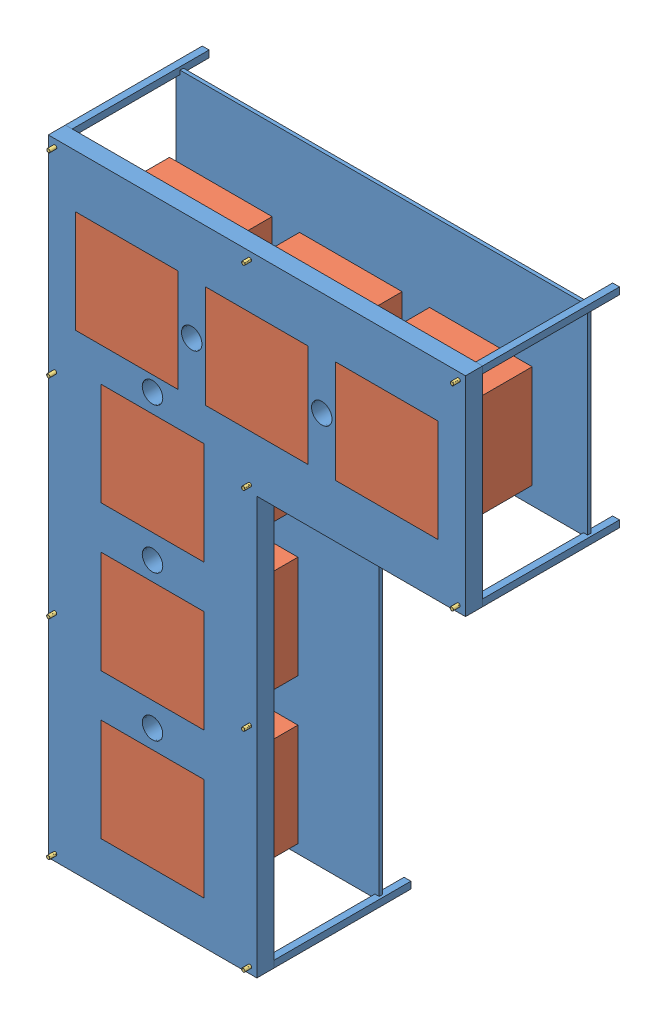
SolidWorks assembly Assemb_rack_small, configuration Default. Lengths in mm.
Overall size (2438.4 3657.6 941.92).
17 component instances, 3 part files, 38 mates.
Components (placement in the parent):
- Rack_small-1: Rack_small [Default] at (-488.5042 3287.9022 2848.7544) size (2438.4 3657.6 900)
- vent_for_RACKS-1: vent_for_RACKS [Default] at (1029.8958 2378.7022 2948.7544) x (0 0 1) z (-1 0 0) size (550 600 600)
- vent_for_RACKS-2: vent_for_RACKS [Default] at (269.8958 2378.7022 2948.7544) x (0 0 1) z (-1 0 0) size (550 600 600)
- vent_for_RACKS-3: vent_for_RACKS [Default] at (420.6958 -119.6978 2948.7544) x (0 0 1) z (-1 0 0) size (550 600 600)
- vent_for_RACKS-4: vent_for_RACKS [Default] at (420.6958 730.3022 2948.7544) x (0 0 1) z (-1 0 0) size (550 600 600)
- vent_for_RACKS-5: vent_for_RACKS [Default] at (420.6958 1580.3022 2948.7544) x (0 0 1) z (-1 0 0) size (550 600 600)
- vent_for_RACKS-6: vent_for_RACKS [Default] at (1789.8958 2378.7022 2948.7544) x (0 0 1) z (-1 0 0) size (550 600 600)
- Bolt-4: Bolt [Default] at (-448.5042 2108.7022 2849.734) x (0 0 -1) z (-0.276507 -0.961012 0) size (84.07 21.62 21.62)
- Bolt-5: Bolt [Default] at (-448.5042 3247.9022 2849.734) x (0 0 -1) z (1 0 0) size (84.07 21.62 21.62)
- Bolt-11: Bolt [Default] at (690.6958 2108.7022 3047.5415) x (0 0 1) z (0.34319 0.939266 0) size (84.07 21.62 21.62)
- Bolt-12: Bolt [Default] at (690.6958 889.5022 3047.5415) x (0 0 1) z (0.926679 0.375854 0) size (84.07 21.62 21.62)
- Bolt-13: Bolt [Default] at (-448.5042 889.5022 3047.5415) x (0 0 1) z (0.919241 0.393696 0) size (84.07 21.62 21.62)
- Bolt-14: Bolt [Default] at (690.6958 -329.6978 3047.5415) x (0 0 1) z (0.023888 0.999715 0) size (84.07 21.62 21.62)
- Bolt-15: Bolt [Default] at (690.6958 3247.9022 3047.5415) x (0 0 1) z (-0.188783 0.982019 0) size (84.07 21.62 21.62)
- Bolt-16: Bolt [Default] at (-448.5042 -329.6978 3047.5415) x (0 0 1) z (0.481387 -0.876508 0) size (84.07 21.62 21.62)
- Bolt-18: Bolt [Default] at (1909.8958 2108.7022 3047.5415) x (0 0 1) z (0.573525 0.819188 0) size (84.07 21.62 21.62)
- Bolt-19: Bolt [Default] at (1909.8958 3247.9022 3047.5415) x (0 0 1) z (-0.910826 0.41279 0) size (84.07 21.62 21.62)
Mates (geometry in assembly coordinates):
- Coincident1: coincident aligned: plane of vent_for_RACKS-3 through (-179.3042 -119.6978 2398.7544) normal (0 0 -1); plane of vent_for_RACKS-4 through (-179.3042 730.3022 2398.7544) normal (0 0 -1)
- Coincident2: coincident aligned: plane of vent_for_RACKS-4 through (-179.3042 730.3022 2398.7544) normal (0 0 -1); plane of vent_for_RACKS-5 through (-179.3042 1580.3022 2398.7544) normal (0 0 -1)
- Coincident3: coincident aligned: plane of vent_for_RACKS-3 through (-179.3042 -119.6978 2398.7544) normal (0 0 -1); plane of vent_for_RACKS-6 through (1189.8958 2378.7022 2398.7544) normal (0 0 -1)
- Coincident4: coincident aligned: plane of vent_for_RACKS-2 through (-330.1042 2378.7022 2398.7544) normal (0 0 -1); plane of vent_for_RACKS-3 through (-179.3042 -119.6978 2398.7544) normal (0 0 -1)
- Coincident5: coincident aligned: plane of vent_for_RACKS-1 through (429.8958 2378.7022 2398.7544) normal (0 0 -1); plane of vent_for_RACKS-3 through (-179.3042 -119.6978 2398.7544) normal (0 0 -1)
- Coincident6: coincident aligned: plane of Rack_small-1 through (-488.5042 3287.9022 2948.7544) normal (0 0 1); plane of vent_for_RACKS-3 through (-179.3042 -119.6978 2948.7544) normal (0 0 1)
- Coincident7: coincident aligned: plane of vent_for_RACKS-3 through (-179.3042 -119.6978 2948.7544) normal (-1 0 0); plane of vent_for_RACKS-4 through (-179.3042 730.3022 2948.7544) normal (-1 0 0)
- Coincident8: coincident aligned: plane of vent_for_RACKS-3 through (-179.3042 -119.6978 2948.7544) normal (-1 0 0); plane of vent_for_RACKS-5 through (-179.3042 1580.3022 2948.7544) normal (-1 0 0)
- Coincident9: coincident aligned: plane of vent_for_RACKS-1 through (429.8958 2978.7022 2948.7544) normal (0 1 0); plane of vent_for_RACKS-6 through (1189.8958 2978.7022 2948.7544) normal (0 1 0)
- Coincident10: coincident aligned: plane of vent_for_RACKS-2 through (-330.1042 2978.7022 2948.7544) normal (0 1 0); plane of vent_for_RACKS-6 through (1189.8958 2978.7022 2948.7544) normal (0 1 0)
- Distance1: distance = 160 mm aligned: plane of vent_for_RACKS-6 through (1789.8958 2378.7022 2948.7544) normal (1 0 0); plane of Rack_small-1 through (1949.8958 2068.7022 2948.7544) normal (1 0 0)
- Distance2: distance = 160 mm anti-aligned: plane of vent_for_RACKS-1 through (1029.8958 2378.7022 2948.7544) normal (1 0 0); plane of vent_for_RACKS-6 through (1189.8958 2378.7022 2948.7544) normal (-1 0 0)
- Distance3: distance = 160 mm anti-aligned: plane of vent_for_RACKS-2 through (269.8958 2378.7022 2948.7544) normal (1 0 0); plane of vent_for_RACKS-1 through (429.8958 2378.7022 2948.7544) normal (-1 0 0)
- Distance4: distance = 250 mm aligned: plane of Rack_small-1 through (730.6958 -369.6978 2948.7544) normal (0 -1 0); plane of vent_for_RACKS-3 through (-179.3042 -119.6978 2948.7544) normal (0 -1 0)
- Distance5: distance = 250 mm anti-aligned: plane of vent_for_RACKS-3 through (-179.3042 480.3022 2948.7544) normal (0 1 0); plane of vent_for_RACKS-4 through (-179.3042 730.3022 2948.7544) normal (0 -1 0)
- Distance6: distance = 250 mm anti-aligned: plane of vent_for_RACKS-4 through (-179.3042 1330.3022 2948.7544) normal (0 1 0); plane of vent_for_RACKS-5 through (-179.3042 1580.3022 2948.7544) normal (0 -1 0)
- Distance7: distance = 310 mm aligned: plane of vent_for_RACKS-6 through (1189.8958 2378.7022 2948.7544) normal (0 -1 0); plane of Rack_small-1 through (1949.8958 2068.7022 2948.7544) normal (0 -1 0)
- Distance8: distance = 310 mm aligned: plane of vent_for_RACKS-5 through (420.6958 1580.3022 2948.7544) normal (1 0 0); plane of Rack_small-1 through (730.6958 2068.7022 2948.7544) normal (1 0 0)
- Concentric1: concentric aligned: circle of Bolt-5; circle of assembly
- Distance9: distance = 40 mm aligned: plane of Bolt-5 through (-448.5042 3258.9022 2988.7544) normal (0 0 1); plane of Rack_small-1 through (-488.5042 3287.9022 2948.7544) normal (0 0 1)
- Concentric2: concentric aligned: circle of Bolt-4; circle of assembly
- Distance10: distance = 40 mm aligned: plane of Rack_small-1 through (-488.5042 3287.9022 2948.7544) normal (0 0 1); plane of Bolt-4 through (-437.9331 2105.6606 2988.7544) normal (0 0 1)
- Concentric4: concentric anti-aligned: circle of Bolt-11; circle of assembly
- Concentric5: concentric anti-aligned: circle of Bolt-12; circle of assembly
- Concentric6: concentric anti-aligned: circle of Bolt-13; circle of assembly
- Concentric10: concentric anti-aligned: circle of Bolt-16; circle of assembly
- Concentric11: concentric anti-aligned: circle of Bolt-14; circle of assembly
- Concentric12: concentric anti-aligned: circle of Bolt-15; circle of assembly
- Concentric13: concentric anti-aligned: circle of Bolt-19; circle of assembly
- Concentric14: concentric anti-aligned: circle of Bolt-18; circle of assembly
- Coincident18: coincident aligned: plane of Bolt-14 through (690.6958 -329.6978 2988.7544) normal (0 0 1); plane of Bolt-16 through (-448.5042 -329.6978 2988.7544) normal (0 0 1)
- Coincident19: coincident aligned: plane of Bolt-12 through (690.6958 889.5022 2988.7544) normal (0 0 1); plane of Bolt-14 through (690.6958 -329.6978 2988.7544) normal (0 0 1)
- Coincident20: coincident aligned: plane of Bolt-11 through (690.6958 2108.7022 2988.7544) normal (0 0 1); plane of Bolt-12 through (690.6958 889.5022 2988.7544) normal (0 0 1)
- Coincident21: coincident aligned: plane of Bolt-11 through (690.6958 2108.7022 2988.7544) normal (0 0 1); plane of Bolt-18 through (1909.8958 2108.7022 2988.7544) normal (0 0 1)
- Coincident22: coincident aligned: plane of Bolt-18 through (1909.8958 2108.7022 2988.7544) normal (0 0 1); plane of Bolt-19 through (1909.8958 3247.9022 2988.7544) normal (0 0 1)
- Coincident23: coincident aligned: plane of Bolt-15 through (690.6958 3247.9022 2988.7544) normal (0 0 1); plane of Bolt-19 through (1909.8958 3247.9022 2988.7544) normal (0 0 1)
- Coincident24: coincident aligned: plane of Bolt-5 through (-448.5042 3258.9022 2988.7544) normal (0 0 1); plane of Bolt-15 through (690.6958 3247.9022 2988.7544) normal (0 0 1)
- Coincident26: coincident aligned: plane of Bolt-5 through (-448.5042 3258.9022 2988.7544) normal (0 0 1); plane of Bolt-13 through (-448.5042 889.5022 2988.7544) normal (0 0 1)
